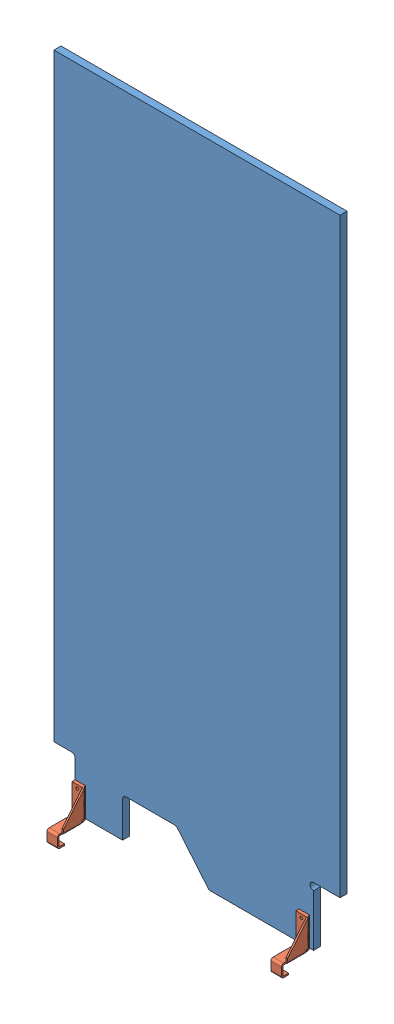
SolidWorks assembly 190216_Playfield_1, configuration Default. Lengths in mm.
Overall size (514.35 1190.94 63.5).
3 component instances, 2 part files, 6 mates.
Components (placement in the parent):
- 190216_BlankPlayfield_1-1: 190216_BlankPlayfield_1 [Default] at (-10628.9777 -13602.9937 6.35) size (514.35 1168.4 12.7)
- 190216_HangerBracket_1-1: 190216_HangerBracket_1 [Default] at (-234.0276 -227.0361 -781.05) x (0 -1 0) z (-1 0 0) size (74.1 50.8 21.97)
- 190216_HangerBracket_1-2: 190216_HangerBracket_1 [Default] at (168.5624 -227.0361 -781.05) x (0 -1 0) z (-1 0 0) size (74.1 50.8 21.97)
Mates (geometry in assembly coordinates):
- Coincident1: coincident anti-aligned: plane of 190216_BlankPlayfield_1-1 through (-161.4249 -521.3989 6.35) normal (0 0 1); plane of 190216_HangerBracket_1-1 through (-253.0776 -533.9316 6.35) normal (0 0 -1)
- Parallel1: parallel anti-aligned: plane of 190216_BlankPlayfield_1-1 through (-253.0755 -585.4936 -6.35) normal (0 -1 0); plane of 190216_HangerBracket_1-1 through (-253.0776 -533.9316 9.271) normal (0 1 0)
- Coincident3: coincident: plane of 190216_BlankPlayfield_1-1 through (-161.4249 -521.3989 6.35) normal (0 0 1); plane of ? through (149.5124 -508.5316 6.35) normal (0 0 -1)
- Parallel2: parallel: plane of ?; plane of ?
- Concentric3: concentric aligned: circle of ?; circle of ?
- Concentric4: concentric aligned: circle of ?; circle of ?
